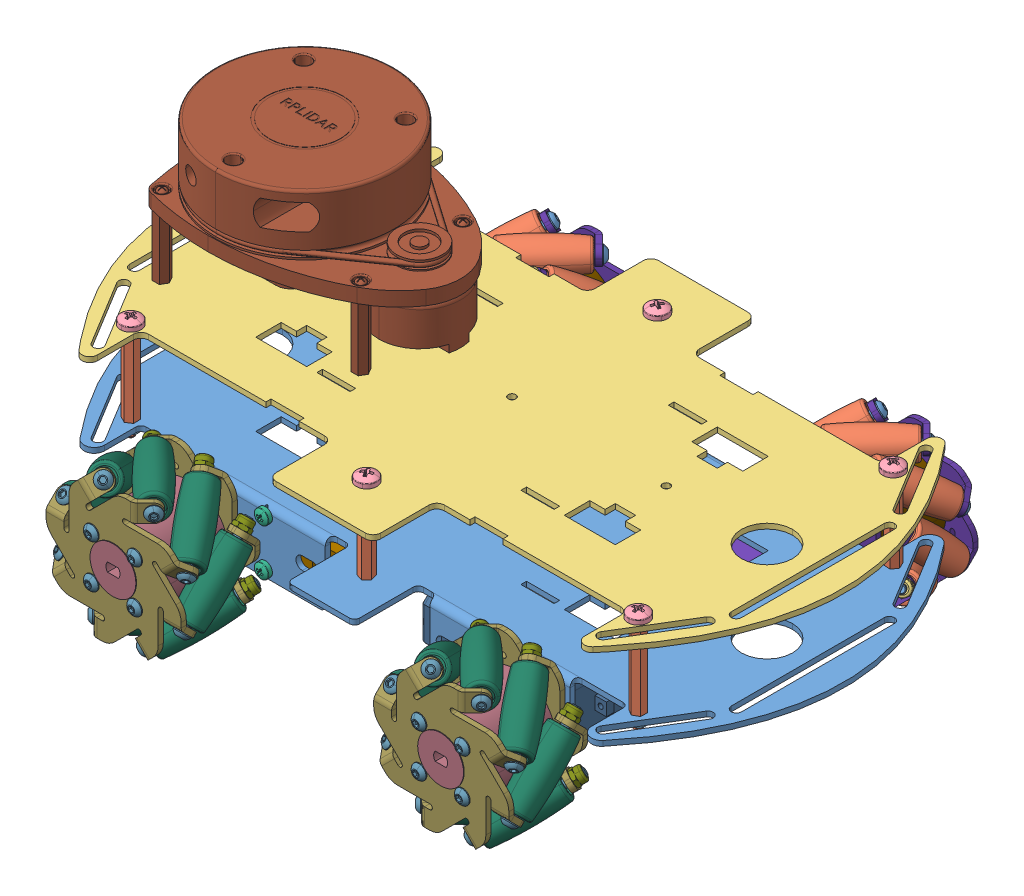
SolidWorks assembly mecanum_car, configuration Default. Lengths in mm.
Overall size (368.82 156.91 257.8).
187 component instances, 21 part files, 13 mates.
Components (placement in the parent):
- chassis.STEP-1: chassis.STEP [Default] at origin size (318.42 61.29 150)
  - chassis.STEP.STEP-1: chassis.STEP.STEP [Default] at origin size (318.42 61.29 150)
    - bottom chassis.STEP.STEP-1: bottom chassis.STEP.STEP [Default] at (-199.6129 0 0) x (1 0 0) z (0 0 -1) size (314.81 25.02 150)
    - supporting hexagon pillar.STEP.STEP-1: supporting hexagon pillar.STEP.STEP [Default] at (-299.1129 2 50) x (0.997179 0 -0.075054) z (0.075054 0 0.997179) size (4.8 36 5.42)
    - Copy of top chasis^chassis.STEP.STEP-1: Copy of top chasis^chassis.STEP.STEP [Default] at (-199.6129 32 0) size (318.42 2 150)
    - supporting hexagon pillar.STEP.STEP-2: supporting hexagon pillar.STEP.STEP [Default] at (-100.1129 2 50) x (0.482568 0 -0.875858) z (0.875858 0 0.482568) size (4.8 36 5.42)
    - supporting hexagon pillar.STEP.STEP-3: supporting hexagon pillar.STEP.STEP [Default] at (-100.1129 2 -50) x (0.886073 0 -0.463545) z (0.463545 0 0.886073) size (4.8 36 5.42)
    - supporting hexagon pillar.STEP.STEP-4: supporting hexagon pillar.STEP.STEP [Default] at (-299.1129 2 -50) x (0.482568 0 -0.875858) z (0.875858 0 0.482568) size (4.8 36 5.42)
    - pan head cross recess screw_iso_ISO 7045 - M4 x 5 - Z - 5N.STEP.STEP-1: pan head cross recess screw_iso_ISO 7045 - M4 x 5 - Z - 5N.STEP.STEP [Default] at (-100.1129 37.1 -50) x (0 -1 0) z (0.075054 0 0.997179) size (8.02 8 8)
    - pan head cross recess screw_iso_ISO 7045 - M4 x 5 - Z - 5N.STEP.STEP-2: pan head cross recess screw_iso_ISO 7045 - M4 x 5 - Z - 5N.STEP.STEP [Default] at (-100.1129 37.1 50) x (0 -1 0) z (0.075054 0 0.997179) size (8.02 8 8)
    - pan head cross recess screw_iso_ISO 7045 - M4 x 5 - Z - 5N.STEP.STEP-3: pan head cross recess screw_iso_ISO 7045 - M4 x 5 - Z - 5N.STEP.STEP [Default] at (-299.1129 37.1 -50) x (0 -1 0) z (0.075054 0 0.997179) size (8.02 8 8)
    - pan head cross recess screw_iso_ISO 7045 - M4 x 5 - Z - 5N.STEP.STEP-4: pan head cross recess screw_iso_ISO 7045 - M4 x 5 - Z - 5N.STEP.STEP [Default] at (-299.1129 37.1 50) x (0 -1 0) z (0.075054 0 0.997179) size (8.02 8 8)
    - hexagon thin nut (ch)_is_IS 1364-4 - M3-N.STEP.STEP-1: hexagon thin nut (ch)_is_IS 1364-4 - M3-N.STEP.STEP [Default] at (-299.1129 -1.8 -50) x (0.997179 0 -0.075054) z (0 -1 0) size (6.36 6.38 1.82)
    - hexagon thin nut (ch)_is_IS 1364-4 - M3-N.STEP.STEP-2: hexagon thin nut (ch)_is_IS 1364-4 - M3-N.STEP.STEP [Default] at (-299.1129 -1.8 50) x (0.997179 0 -0.075054) z (0 -1 0) size (6.36 6.38 1.82)
    - hexagon thin nut (ch)_is_IS 1364-4 - M3-N.STEP.STEP-3: hexagon thin nut (ch)_is_IS 1364-4 - M3-N.STEP.STEP [Default] at (-100.1129 -1.8 50) x (0.997179 0 -0.075054) z (0 -1 0) size (6.36 6.38 1.82)
    - hexagon thin nut (ch)_is_IS 1364-4 - M3-N.STEP.STEP-4: hexagon thin nut (ch)_is_IS 1364-4 - M3-N.STEP.STEP [Default] at (-100.1129 -1.8 -50) x (0.997179 0 -0.075054) z (0 -1 0) size (6.36 6.38 1.82)
    - pan head cross recess screw_iso_ISO 7045 - M3 x 30 - Z - 30S.STEP.STEP-1: pan head cross recess screw_iso_ISO 7045 - M3 x 30 - Z - 30S.STEP.STEP [Default] at (-155.6129 -20.0527 -55.1366) x (0 0 1) z (-0.913722 -0.40634 0) size (32.35 5.6 5.6)
    - pan head cross recess screw_iso_ISO 7045 - M3 x 30 - Z - 30S.STEP.STEP-2: pan head cross recess screw_iso_ISO 7045 - M3 x 30 - Z - 30S.STEP.STEP [Default] at (-155.6129 -1.6927 -55.1366) x (0 0 1) z (-0.913722 -0.40634 0) size (32.35 5.6 5.6)
    - pan head cross recess screw_iso_ISO 7045 - M3 x 30 - Z - 30S.STEP.STEP-3: pan head cross recess screw_iso_ISO 7045 - M3 x 30 - Z - 30S.STEP.STEP [Default] at (-243.6129 -20.0527 -55.1366) x (0 0 1) z (-0.913722 -0.40634 0) size (32.35 5.6 5.6)
    - pan head cross recess screw_iso_ISO 7045 - M3 x 30 - Z - 30S.STEP.STEP-4: pan head cross recess screw_iso_ISO 7045 - M3 x 30 - Z - 30S.STEP.STEP [Default] at (-243.6129 -1.6927 -55.1366) x (0 0 1) z (-0.913722 -0.40634 0) size (32.35 5.6 5.6)
    - pan head cross recess screw_iso_ISO 7045 - M3 x 30 - Z - 30S.STEP.STEP-5: pan head cross recess screw_iso_ISO 7045 - M3 x 30 - Z - 30S.STEP.STEP [Default] at (-243.6129 -20.0527 55.1366) x (0 0 -1) z (0.924865 -0.380295 0) size (32.35 5.6 5.6)
    - pan head cross recess screw_iso_ISO 7045 - M3 x 30 - Z - 30S.STEP.STEP-6: pan head cross recess screw_iso_ISO 7045 - M3 x 30 - Z - 30S.STEP.STEP [Default] at (-243.6129 -1.6927 55.1366) x (0 0 -1) z (0.924865 -0.380295 0) size (32.35 5.6 5.6)
    - pan head cross recess screw_iso_ISO 7045 - M3 x 30 - Z - 30S.STEP.STEP-7: pan head cross recess screw_iso_ISO 7045 - M3 x 30 - Z - 30S.STEP.STEP [Default] at (-155.6129 -20.0527 55.1366) x (0 0 -1) z (0.924865 -0.380295 0) size (32.35 5.6 5.6)
    - pan head cross recess screw_iso_ISO 7045 - M3 x 30 - Z - 30S.STEP.STEP-8: pan head cross recess screw_iso_ISO 7045 - M3 x 30 - Z - 30S.STEP.STEP [Default] at (-155.6129 -1.6927 55.1366) x (0 0 -1) z (0.924865 -0.380295 0) size (32.35 5.6 5.6)
    - hexagon thin nut (ch)_is_IS 1364-4 - M3-N.STEP.STEP-5: hexagon thin nut (ch)_is_IS 1364-4 - M3-N.STEP.STEP [Default] at (-155.6129 -20.1883 30.4366) x (0.939963 0.341277 0) z (0 0 -1) size (6.36 6.38 1.82)
    - hexagon thin nut (ch)_is_IS 1364-4 - M3-N.STEP.STEP-6: hexagon thin nut (ch)_is_IS 1364-4 - M3-N.STEP.STEP [Default] at (-155.6129 -1.6883 30.4366) x (0.939963 0.341277 0) z (0 0 -1) size (6.36 6.38 1.82)
    - hexagon thin nut (ch)_is_IS 1364-4 - M3-N.STEP.STEP-7: hexagon thin nut (ch)_is_IS 1364-4 - M3-N.STEP.STEP [Default] at (-243.6129 -20.057 30.4366) x (0.939963 0.341277 0) z (0 0 -1) size (6.36 6.38 1.82)
    - hexagon thin nut (ch)_is_IS 1364-4 - M3-N.STEP.STEP-8: hexagon thin nut (ch)_is_IS 1364-4 - M3-N.STEP.STEP [Default] at (-243.6129 -1.557 30.4366) x (0.939963 0.341277 0) z (0 0 -1) size (6.36 6.38 1.82)
    - hexagon thin nut (ch)_is_IS 1364-4 - M3-N.STEP.STEP-9: hexagon thin nut (ch)_is_IS 1364-4 - M3-N.STEP.STEP [Default] at (-243.6129 -20.1883 -30.4366) size (6.36 6.38 1.82)
    - hexagon thin nut (ch)_is_IS 1364-4 - M3-N.STEP.STEP-10: hexagon thin nut (ch)_is_IS 1364-4 - M3-N.STEP.STEP [Default] at (-243.6129 -1.6883 -30.4366) size (6.36 6.38 1.82)
    - hexagon thin nut (ch)_is_IS 1364-4 - M3-N.STEP.STEP-11: hexagon thin nut (ch)_is_IS 1364-4 - M3-N.STEP.STEP [Default] at (-155.6129 -20.057 -30.4366) size (6.36 6.38 1.82)
    - hexagon thin nut (ch)_is_IS 1364-4 - M3-N.STEP.STEP-12: hexagon thin nut (ch)_is_IS 1364-4 - M3-N.STEP.STEP [Default] at (-155.6129 -1.557 -30.4366) size (6.36 6.38 1.82)
    - supporting hexagon pillar.STEP.STEP-5: supporting hexagon pillar.STEP.STEP [Default] at (-199.6129 2 -57) x (0.376997 0 -0.926214) z (0.926214 0 0.376997) size (4.8 36 5.42)
    - supporting hexagon pillar.STEP.STEP-6: supporting hexagon pillar.STEP.STEP [Default] at (-199.6129 2 57) x (-0.715077 0 -0.699046) z (0.699046 0 -0.715077) size (4.8 36 5.42)
    - hexagon thin nut (ch)_is_IS 1364-4 - M3-N.STEP.STEP-13: hexagon thin nut (ch)_is_IS 1364-4 - M3-N.STEP.STEP [Default] at (-199.6129 -1.8 57) x (0.981594 0 -0.190977) z (0 -1 0) size (6.36 6.38 1.82)
    - hexagon thin nut (ch)_is_IS 1364-4 - M3-N.STEP.STEP-14: hexagon thin nut (ch)_is_IS 1364-4 - M3-N.STEP.STEP [Default] at (-199.6129 -1.8 -57) x (0.939935 0 -0.341353) z (0 -1 0) size (6.36 6.38 1.82)
    - pan head cross recess screw_iso_ISO 7045 - M4 x 5 - Z - 5N.STEP.STEP-5: pan head cross recess screw_iso_ISO 7045 - M4 x 5 - Z - 5N.STEP.STEP [Default] at (-199.6129 37.1 -57) x (0 -1 0) z (0.875858 0 0.482568) size (8.02 8 8)
    - pan head cross recess screw_iso_ISO 7045 - M4 x 5 - Z - 5N.STEP.STEP-6: pan head cross recess screw_iso_ISO 7045 - M4 x 5 - Z - 5N.STEP.STEP [Default] at (-199.6129 37.1 57) x (0 -1 0) z (0.463545 0 0.886073) size (8.02 8 8)
  - Motor1.step.STEP-1: Motor1.step.STEP [Default] at (-275.1129 -22.1883 -32.2366) size (66.5 22.5 38.5)
  - Motor2.step.STEP-1: Motor2.step.STEP [Default] at (-124.1129 0.443 -32.2366) x (-1 0 0) z (0 0 1) size (66.5 22.5 38.5)
  - Motor3.step.STEP-1: Motor3.step.STEP [Default] at (-275.1129 0.443 32.2366) x (1 0 0) z (0 0 -1) size (66.5 22.5 38.5)
  - Motor4.step.STEP-1: Motor4.step.STEP [Default] at (-124.1129 -22.1883 32.2366) x (-1 0 0) z (0 0 -1) size (66.5 22.5 38.5)
- rplidarA1.step-1: rplidarA1.step [Default] at (-280.315 65.1 0.5496) size (96.17 54.6 70)
- left_forward.STEP-1: left_forward.STEP [Default] at (-233.0265 -21.1144 212.4082) x (-0.184533 -0.709257 -0.680369) z (0.944404 -0.319631 0.077057) size (70.26 72.13 71.93)
  - Mirrormecanum wheels.STEP.STEP-1: Mirrormecanum wheels.STEP.STEP [Default] at (81.7182 87.2657 -41.8289) x (0.184533 -0.27212 -0.944404) z (-0.680369 -0.728807 0.077057) size (55.02 55.02 7.58)
  - Mirrorshaft.STEP.STEP-1: Mirrorshaft.STEP.STEP [Default] at (90.9032 97.1046 -42.8692) x (-0.184533 0.27212 0.944404) z (0.680369 0.728807 -0.077057) size (32 32 31.5)
  - Mirrormecanum wheels.STEP.STEP-2: Mirrormecanum wheels.STEP.STEP [Default] at (100.0882 106.9435 -43.9095) x (-0.709257 0.628323 -0.319631) z (0.680369 0.728807 -0.077057) size (55.02 55.02 7.58)
  - Mirrorbolt.STEP.STEP-1: Mirrorbolt.STEP.STEP [Default] at (87.2167 86.0621 -16.0538) x (-0.020427 0.959636 -0.280501) z (0.96794 0.089234 0.234795) size (38.65 5.7 5.7)
  - MirrorRoller.STEP.STEP-1: MirrorRoller.STEP.STEP [Default] at (86.8493 103.3226 -21.099) x (-0.020427 0.959636 -0.280501) z (0.96794 0.089234 0.234795) size (28 12 12)
  - Mirrorbolt.STEP.STEP-2: Mirrorbolt.STEP.STEP [Default] at (86.8189 76.965 -46.8491) x (0.680369 0.728807 -0.077057) z (-0.018616 -0.087924 -0.995953) size (38.65 5.7 5.7)
  - Mirrortorque nut 08_iso_ISO 10511-M3-N.STEP.STEP-1: Mirrortorque nut 08_iso_ISO 10511-M3-N.STEP.STEP [Default] at (110.0875 101.8903 -49.4844) x (-0.185961 0.06998 -0.980062) z (-0.680369 -0.728807 0.077057) size (6.36 6.38 3.91)
  - Mirrortorque nut 08_iso_ISO 10511-M3-N.STEP.STEP-2: Mirrortorque nut 08_iso_ISO 10511-M3-N.STEP.STEP [Default] at (86.1032 120.5687 -26.214) x (0.873571 0.153587 0.461828) z (0.020427 -0.959636 0.280501) size (6.36 6.38 3.91)
  - Mirrorbolt.STEP.STEP-3: Mirrorbolt.STEP.STEP [Default] at (98.9986 73.9021 -27.0356) x (0.034198 0.965566 0.257899) z (0.950888 0.047997 -0.305791) size (38.65 5.7 5.7)
  - Mirrorbolt.STEP.STEP-4: Mirrorbolt.STEP.STEP [Default] at (101.0077 69.945 -46.7228) x (0.350609 0.707763 0.613307) z (0.657996 0.279839 -0.699094) size (38.65 5.7 5.7)
  - Mirrorbolt.STEP.STEP-5: Mirrorbolt.STEP.STEP [Default] at (92.0671 76.5089 -63.5829) x (0.743455 0.337243 0.57753) z (0.260835 0.648951 -0.714722) size (38.65 5.7 5.7)
  - Mirrorbolt.STEP.STEP-6: Mirrorbolt.STEP.STEP [Default] at (77.414 89.7486 -67.7394) x (0.982614 0.071053 0.171526) z (-0.007942 0.939111 -0.343521) size (38.65 5.7 5.7)
  - Mirrorbolt.STEP.STEP-7: Mirrorbolt.STEP.STEP [Default] at (65.632 101.9086 -56.7575) x (0.927989 0.065123 -0.366873) z (0.00911 0.980348 0.197064) size (38.65 5.7 5.7)
  - Mirrorbolt.STEP.STEP-8: Mirrorbolt.STEP.STEP [Default] at (63.6229 105.8657 -37.0704) x (0.611578 0.322927 -0.722281) z (0.302003 0.748506 0.590367) size (38.65 5.7 5.7)
  - Mirrorbolt.STEP.STEP-9: Mirrorbolt.STEP.STEP [Default] at (72.5636 99.3019 -20.2103) x (0.218732 0.693446 -0.686505) z (0.699163 0.379394 0.605995) size (38.65 5.7 5.7)
  - Mirrortorque nut 08_iso_ISO 10511-M3-N.STEP.STEP-3: Mirrortorque nut 08_iso_ISO 10511-M3-N.STEP.STEP [Default] at (99.872 108.6244 -17.6135) x (0.997731 -0.018009 -0.064876) z (-0.034198 -0.965566 -0.257899) size (6.36 6.38 3.91)
  - Mirrortorque nut 08_iso_ISO 10511-M3-N.STEP.STEP-4: Mirrortorque nut 08_iso_ISO 10511-M3-N.STEP.STEP [Default] at (113.3894 95.2906 -24.3739) x (0.804741 0.107283 -0.583851) z (-0.350609 -0.707763 -0.613307) size (6.36 6.38 3.91)
  - Mirrortorque nut 08_iso_ISO 10511-M3-N.STEP.STEP-5: Mirrortorque nut 08_iso_ISO 10511-M3-N.STEP.STEP [Default] at (118.7372 88.378 -42.5352) x (0.407653 0.456068 -0.791089) z (-0.743455 -0.337243 -0.57753) size (6.36 6.38 3.91)
  - Mirrortorque nut 08_iso_ISO 10511-M3-N.STEP.STEP-6: Mirrortorque nut 08_iso_ISO 10511-M3-N.STEP.STEP [Default] at (112.7827 91.936 -61.4588) x (0.039074 0.824034 -0.565191) z (-0.982614 -0.071053 -0.171526) size (6.36 6.38 3.91)
  - Mirrortorque nut 08_iso_ISO 10511-M3-N.STEP.STEP-7: Mirrortorque nut 08_iso_ISO 10511-M3-N.STEP.STEP [Default] at (99.0139 103.8803 -70.0593) x (-0.085085 0.99563 -0.038487) z (-0.927989 -0.065123 0.366873) size (6.36 6.38 3.91)
  - Mirrortorque nut 08_iso_ISO 10511-M3-N.STEP.STEP-8: Mirrortorque nut 08_iso_ISO 10511-M3-N.STEP.STEP [Default] at (85.4965 117.2141 -63.2989) x (0.107904 0.870338 0.480488) z (-0.611578 -0.322927 0.722281) size (6.36 6.38 3.91)
  - Mirrortorque nut 08_iso_ISO 10511-M3-N.STEP.STEP-9: Mirrortorque nut 08_iso_ISO 10511-M3-N.STEP.STEP [Default] at (80.1487 124.1267 -45.1376) x (0.504993 0.521552 0.687725) z (-0.218732 -0.693446 0.686505) size (6.36 6.38 3.91)
  - MirrorRoller.STEP.STEP-2: MirrorRoller.STEP.STEP [Default] at (99.6137 91.2692 -22.3969) x (0.034198 0.965566 0.257899) z (0.950888 0.047997 -0.305791) size (28 12 12)
  - MirrorRoller.STEP.STEP-3: MirrorRoller.STEP.STEP [Default] at (107.3139 82.6752 -35.6916) x (0.350609 0.707763 0.613307) z (0.657996 0.279839 -0.699094) size (28 12 12)
  - MirrorRoller.STEP.STEP-4: MirrorRoller.STEP.STEP [Default] at (105.4392 82.5747 -53.1951) x (0.743455 0.337243 0.57753) z (0.260835 0.648951 -0.714722) size (28 12 12)
  - MirrorRoller.STEP.STEP-5: MirrorRoller.STEP.STEP [Default] at (95.0877 91.0266 -64.6542) x (0.982614 0.071053 0.171526) z (-0.007942 0.939111 -0.343521) size (28 12 12)
  - MirrorRoller.STEP.STEP-6: MirrorRoller.STEP.STEP [Default] at (82.3233 103.0799 -63.3563) x (0.927989 0.065123 -0.366873) z (0.00911 0.980348 0.197064) size (28 12 12)
  - MirrorRoller.STEP.STEP-7: MirrorRoller.STEP.STEP [Default] at (74.6231 111.674 -50.0616) x (0.611578 0.322927 -0.722281) z (0.302003 0.748506 0.590367) size (28 12 12)
  - MirrorRoller.STEP.STEP-8: MirrorRoller.STEP.STEP [Default] at (76.4978 111.7745 -32.5581) x (0.218732 0.693446 -0.686505) z (0.699163 0.379394 0.605995) size (28 12 12)
  - Mirrorbolt.STEP.STEP-10: Mirrorbolt.STEP.STEP [Default] at (83.6873 81.5831 -30.822) x (0.680369 0.728807 -0.077057) z (0.168933 -0.258274 -0.951187) size (38.65 5.7 5.7)
  - Mirrorbolt.STEP.STEP-11: Mirrorbolt.STEP.STEP [Default] at (71.6508 92.2461 -36.2463) x (0.680369 0.728807 -0.077057) z (0.340283 -0.407278 -0.847545) size (38.65 5.7 5.7)
  - Mirrorbolt.STEP.STEP-12: Mirrorbolt.STEP.STEP [Default] at (74.7824 87.6281 -52.2734) x (0.680369 0.728807 -0.077057) z (0.481066 -0.523448 -0.703262) size (38.65 5.7 5.7)
  - Mirrortorque nut 08_iso_ISO 10511-M3-N.STEP.STEP-10: Mirrortorque nut 08_iso_ISO 10511-M3-N.STEP.STEP [Default] at (98.051 112.5533 -54.9087) x (0.533825 -0.420797 0.733458) z (-0.680369 -0.728807 0.077057) size (6.36 6.38 3.91)
  - Mirrortorque nut 08_iso_ISO 10511-M3-N.STEP.STEP-11: Mirrortorque nut 08_iso_ISO 10511-M3-N.STEP.STEP [Default] at (106.9559 106.5083 -33.4573) x (0.321016 -0.201847 0.925314) z (-0.680369 -0.728807 0.077057) size (6.36 6.38 3.91)
  - Mirrortorque nut 08_iso_ISO 10511-M3-N.STEP.STEP-12: Mirrortorque nut 08_iso_ISO 10511-M3-N.STEP.STEP [Default] at (94.9194 117.1713 -38.8817) x (0.017858 0.088626 0.995905) z (-0.680369 -0.728807 0.077057) size (6.36 6.38 3.91)
- right_forward.STEP-1: right_forward.STEP [Default] at (-233.0265 -21.1144 -212.4082) x (-0.184533 -0.709257 0.680369) z (-0.944404 0.319631 0.077057) size (70.26 72.13 71.93)
  - MirrorMirrormecanum wheels.STEP.STEP.STEP-1: MirrorMirrormecanum wheels.STEP.STEP.STEP [Default] at (81.7182 87.2657 41.8289) x (0.184533 -0.27212 0.944404) z (0.680369 0.728807 0.077057) size (55.02 55.02 7.58)
  - MirrorMirrorshaft.STEP.STEP.STEP-1: MirrorMirrorshaft.STEP.STEP.STEP [Default] at (90.9032 97.1046 42.8692) x (-0.184533 0.27212 -0.944404) z (-0.680369 -0.728807 -0.077057) size (32 32 31.5)
  - MirrorMirrormecanum wheels.STEP.STEP.STEP-2: MirrorMirrormecanum wheels.STEP.STEP.STEP [Default] at (100.0882 106.9435 43.9095) x (-0.709257 0.628323 0.319631) z (-0.680369 -0.728807 -0.077057) size (55.02 55.02 7.58)
  - MirrorMirrorbolt.STEP.STEP.STEP-1: MirrorMirrorbolt.STEP.STEP.STEP [Default] at (87.2167 86.0621 16.0538) x (-0.020427 0.959636 0.280501) z (-0.96794 -0.089234 0.234795) size (38.65 5.7 5.7)
  - MirrorMirrorRoller.STEP.STEP.STEP-1: MirrorMirrorRoller.STEP.STEP.STEP [Default] at (86.8493 103.3226 21.099) x (-0.020427 0.959636 0.280501) z (-0.96794 -0.089234 0.234795) size (28 12 12)
  - MirrorMirrorbolt.STEP.STEP.STEP-2: MirrorMirrorbolt.STEP.STEP.STEP [Default] at (86.8189 76.965 46.8491) x (0.680369 0.728807 0.077057) z (0.018616 0.087924 -0.995953) size (38.65 5.7 5.7)
  - MirrorMirrortorque nut 08_iso_ISO 10511-M3-N.STEP.STEP.STEP-1: MirrorMirrortorque nut 08_iso_ISO 10511-M3-N.STEP.STEP.STEP [Default] at (110.0875 101.8903 49.4844) x (-0.185961 0.06998 0.980062) z (0.680369 0.728807 0.077057) size (6.36 6.36 3.91)
  - MirrorMirrortorque nut 08_iso_ISO 10511-M3-N.STEP.STEP.STEP-2: MirrorMirrortorque nut 08_iso_ISO 10511-M3-N.STEP.STEP.STEP [Default] at (86.1032 120.5687 26.214) x (0.873571 0.153587 -0.461828) z (-0.020427 0.959636 0.280501) size (6.36 6.36 3.91)
  - MirrorMirrorbolt.STEP.STEP.STEP-3: MirrorMirrorbolt.STEP.STEP.STEP [Default] at (98.9986 73.9021 27.0356) x (0.034198 0.965566 -0.257899) z (-0.950888 -0.047997 -0.305791) size (38.65 5.7 5.7)
  - MirrorMirrorbolt.STEP.STEP.STEP-4: MirrorMirrorbolt.STEP.STEP.STEP [Default] at (101.0077 69.945 46.7228) x (0.350609 0.707763 -0.613307) z (-0.657996 -0.279839 -0.699094) size (38.65 5.7 5.7)
  - MirrorMirrorbolt.STEP.STEP.STEP-5: MirrorMirrorbolt.STEP.STEP.STEP [Default] at (92.0671 76.5089 63.5829) x (0.743455 0.337243 -0.57753) z (-0.260835 -0.648951 -0.714722) size (38.65 5.7 5.7)
  - MirrorMirrorbolt.STEP.STEP.STEP-6: MirrorMirrorbolt.STEP.STEP.STEP [Default] at (77.414 89.7486 67.7394) x (0.982614 0.071053 -0.171526) z (0.007942 -0.939111 -0.343521) size (38.65 5.7 5.7)
  - MirrorMirrorbolt.STEP.STEP.STEP-7: MirrorMirrorbolt.STEP.STEP.STEP [Default] at (65.632 101.9086 56.7575) x (0.927989 0.065123 0.366873) z (-0.00911 -0.980348 0.197064) size (38.65 5.7 5.7)
  - MirrorMirrorbolt.STEP.STEP.STEP-8: MirrorMirrorbolt.STEP.STEP.STEP [Default] at (63.6229 105.8657 37.0704) x (0.611578 0.322927 0.722281) z (-0.302003 -0.748506 0.590367) size (38.65 5.7 5.7)
  - MirrorMirrorbolt.STEP.STEP.STEP-9: MirrorMirrorbolt.STEP.STEP.STEP [Default] at (72.5636 99.3019 20.2103) x (0.218732 0.693446 0.686505) z (-0.699163 -0.379394 0.605995) size (38.65 5.7 5.7)
  - MirrorMirrortorque nut 08_iso_ISO 10511-M3-N.STEP.STEP.STEP-3: MirrorMirrortorque nut 08_iso_ISO 10511-M3-N.STEP.STEP.STEP [Default] at (99.872 108.6244 17.6135) x (0.997731 -0.018009 0.064876) z (0.034198 0.965566 -0.257899) size (6.36 6.36 3.91)
  - MirrorMirrortorque nut 08_iso_ISO 10511-M3-N.STEP.STEP.STEP-4: MirrorMirrortorque nut 08_iso_ISO 10511-M3-N.STEP.STEP.STEP [Default] at (113.3894 95.2906 24.3739) x (0.804741 0.107283 0.583851) z (0.350609 0.707763 -0.613307) size (6.36 6.36 3.91)
  - MirrorMirrortorque nut 08_iso_ISO 10511-M3-N.STEP.STEP.STEP-5: MirrorMirrortorque nut 08_iso_ISO 10511-M3-N.STEP.STEP.STEP [Default] at (118.7372 88.378 42.5352) x (0.407653 0.456068 0.791089) z (0.743455 0.337243 -0.57753) size (6.36 6.36 3.91)
  - MirrorMirrortorque nut 08_iso_ISO 10511-M3-N.STEP.STEP.STEP-6: MirrorMirrortorque nut 08_iso_ISO 10511-M3-N.STEP.STEP.STEP [Default] at (112.7827 91.936 61.4588) x (0.039074 0.824034 0.565191) z (0.982614 0.071053 -0.171526) size (6.36 6.36 3.91)
  - MirrorMirrortorque nut 08_iso_ISO 10511-M3-N.STEP.STEP.STEP-7: MirrorMirrortorque nut 08_iso_ISO 10511-M3-N.STEP.STEP.STEP [Default] at (99.0139 103.8803 70.0593) x (-0.085085 0.99563 0.038487) z (0.927989 0.065123 0.366873) size (6.36 6.36 3.91)
  - MirrorMirrortorque nut 08_iso_ISO 10511-M3-N.STEP.STEP.STEP-8: MirrorMirrortorque nut 08_iso_ISO 10511-M3-N.STEP.STEP.STEP [Default] at (85.4965 117.2141 63.2989) x (0.107904 0.870338 -0.480488) z (0.611578 0.322927 0.722281) size (6.36 6.36 3.91)
  - MirrorMirrortorque nut 08_iso_ISO 10511-M3-N.STEP.STEP.STEP-9: MirrorMirrortorque nut 08_iso_ISO 10511-M3-N.STEP.STEP.STEP [Default] at (80.1487 124.1267 45.1376) x (0.504993 0.521552 -0.687725) z (0.218732 0.693446 0.686505) size (6.36 6.36 3.91)
  - MirrorMirrorRoller.STEP.STEP.STEP-2: MirrorMirrorRoller.STEP.STEP.STEP [Default] at (99.6137 91.2692 22.3969) x (0.034198 0.965566 -0.257899) z (-0.950888 -0.047997 -0.305791) size (28 12 12)
  - MirrorMirrorRoller.STEP.STEP.STEP-3: MirrorMirrorRoller.STEP.STEP.STEP [Default] at (107.3139 82.6752 35.6916) x (0.350609 0.707763 -0.613307) z (-0.657996 -0.279839 -0.699094) size (28 12 12)
  - MirrorMirrorRoller.STEP.STEP.STEP-4: MirrorMirrorRoller.STEP.STEP.STEP [Default] at (105.4392 82.5747 53.1951) x (0.743455 0.337243 -0.57753) z (-0.260835 -0.648951 -0.714722) size (28 12 12)
  - MirrorMirrorRoller.STEP.STEP.STEP-5: MirrorMirrorRoller.STEP.STEP.STEP [Default] at (95.0877 91.0266 64.6542) x (0.982614 0.071053 -0.171526) z (0.007942 -0.939111 -0.343521) size (28 12 12)
  - MirrorMirrorRoller.STEP.STEP.STEP-6: MirrorMirrorRoller.STEP.STEP.STEP [Default] at (82.3233 103.0799 63.3563) x (0.927989 0.065123 0.366873) z (-0.00911 -0.980348 0.197064) size (28 12 12)
  - MirrorMirrorRoller.STEP.STEP.STEP-7: MirrorMirrorRoller.STEP.STEP.STEP [Default] at (74.6231 111.674 50.0616) x (0.611578 0.322927 0.722281) z (-0.302003 -0.748506 0.590367) size (28 12 12)
  - MirrorMirrorRoller.STEP.STEP.STEP-8: MirrorMirrorRoller.STEP.STEP.STEP [Default] at (76.4978 111.7745 32.5581) x (0.218732 0.693446 0.686505) z (-0.699163 -0.379394 0.605995) size (28 12 12)
  - MirrorMirrorbolt.STEP.STEP.STEP-10: MirrorMirrorbolt.STEP.STEP.STEP [Default] at (83.6873 81.5831 30.822) x (0.680369 0.728807 0.077057) z (-0.168933 0.258274 -0.951187) size (38.65 5.7 5.7)
  - MirrorMirrorbolt.STEP.STEP.STEP-11: MirrorMirrorbolt.STEP.STEP.STEP [Default] at (71.6508 92.2461 36.2463) x (0.680369 0.728807 0.077057) z (-0.340283 0.407278 -0.847545) size (38.65 5.7 5.7)
  - MirrorMirrorbolt.STEP.STEP.STEP-12: MirrorMirrorbolt.STEP.STEP.STEP [Default] at (74.7824 87.6281 52.2734) x (0.680369 0.728807 0.077057) z (-0.481066 0.523448 -0.703262) size (38.65 5.7 5.7)
  - MirrorMirrortorque nut 08_iso_ISO 10511-M3-N.STEP.STEP.STEP-10: MirrorMirrortorque nut 08_iso_ISO 10511-M3-N.STEP.STEP.STEP [Default] at (98.051 112.5533 54.9087) x (0.533825 -0.420797 -0.733458) z (0.680369 0.728807 0.077057) size (6.36 6.36 3.91)
  - MirrorMirrortorque nut 08_iso_ISO 10511-M3-N.STEP.STEP.STEP-11: MirrorMirrortorque nut 08_iso_ISO 10511-M3-N.STEP.STEP.STEP [Default] at (106.9559 106.5083 33.4573) x (0.321016 -0.201847 -0.925314) z (0.680369 0.728807 0.077057) size (6.36 6.36 3.91)
  - MirrorMirrortorque nut 08_iso_ISO 10511-M3-N.STEP.STEP.STEP-12: MirrorMirrortorque nut 08_iso_ISO 10511-M3-N.STEP.STEP.STEP [Default] at (94.9194 117.1713 38.8817) x (0.017858 0.088626 -0.995905) z (0.680369 0.728807 0.077057) size (6.36 6.36 3.91)
- left_back.STEP-1: left_back.STEP [Default] at (-104.5265 -21.1144 212.4082) x (-0.184533 -0.709257 -0.680369) z (0.944404 -0.319631 0.077057) size (70.26 72.13 71.93)
  - Mirrormecanum wheels.STEP.STEP-1: Mirrormecanum wheels.STEP.STEP [Default] at (81.7182 87.2657 -41.8289) x (0.184533 -0.27212 -0.944404) z (-0.680369 -0.728807 0.077057) size (55.02 55.02 7.58)
  - Mirrorshaft.STEP.STEP-1: Mirrorshaft.STEP.STEP [Default] at (90.9032 97.1046 -42.8692) x (-0.184533 0.27212 0.944404) z (0.680369 0.728807 -0.077057) size (32 32 31.5)
  - Mirrormecanum wheels.STEP.STEP-2: Mirrormecanum wheels.STEP.STEP [Default] at (100.0882 106.9435 -43.9095) x (-0.709257 0.628323 -0.319631) z (0.680369 0.728807 -0.077057) size (55.02 55.02 7.58)
  - Mirrorbolt.STEP.STEP-1: Mirrorbolt.STEP.STEP [Default] at (87.2167 86.0621 -16.0538) x (-0.020427 0.959636 -0.280501) z (0.96794 0.089234 0.234795) size (38.65 5.7 5.7)
  - MirrorRoller.STEP.STEP-1: MirrorRoller.STEP.STEP [Default] at (86.8493 103.3226 -21.099) x (-0.020427 0.959636 -0.280501) z (0.96794 0.089234 0.234795) size (28 12 12)
  - Mirrorbolt.STEP.STEP-2: Mirrorbolt.STEP.STEP [Default] at (86.8189 76.965 -46.8491) x (0.680369 0.728807 -0.077057) z (-0.018616 -0.087924 -0.995953) size (38.65 5.7 5.7)
  - Mirrortorque nut 08_iso_ISO 10511-M3-N.STEP.STEP-1: Mirrortorque nut 08_iso_ISO 10511-M3-N.STEP.STEP [Default] at (110.0875 101.8903 -49.4844) x (-0.185961 0.06998 -0.980062) z (-0.680369 -0.728807 0.077057) size (6.36 6.38 3.91)
  - Mirrortorque nut 08_iso_ISO 10511-M3-N.STEP.STEP-2: Mirrortorque nut 08_iso_ISO 10511-M3-N.STEP.STEP [Default] at (86.1032 120.5687 -26.214) x (0.873571 0.153587 0.461828) z (0.020427 -0.959636 0.280501) size (6.36 6.38 3.91)
  - Mirrorbolt.STEP.STEP-3: Mirrorbolt.STEP.STEP [Default] at (98.9986 73.9021 -27.0356) x (0.034198 0.965566 0.257899) z (0.950888 0.047997 -0.305791) size (38.65 5.7 5.7)
  - Mirrorbolt.STEP.STEP-4: Mirrorbolt.STEP.STEP [Default] at (101.0077 69.945 -46.7228) x (0.350609 0.707763 0.613307) z (0.657996 0.279839 -0.699094) size (38.65 5.7 5.7)
  - Mirrorbolt.STEP.STEP-5: Mirrorbolt.STEP.STEP [Default] at (92.0671 76.5089 -63.5829) x (0.743455 0.337243 0.57753) z (0.260835 0.648951 -0.714722) size (38.65 5.7 5.7)
  - Mirrorbolt.STEP.STEP-6: Mirrorbolt.STEP.STEP [Default] at (77.414 89.7486 -67.7394) x (0.982614 0.071053 0.171526) z (-0.007942 0.939111 -0.343521) size (38.65 5.7 5.7)
  - Mirrorbolt.STEP.STEP-7: Mirrorbolt.STEP.STEP [Default] at (65.632 101.9086 -56.7575) x (0.927989 0.065123 -0.366873) z (0.00911 0.980348 0.197064) size (38.65 5.7 5.7)
  - Mirrorbolt.STEP.STEP-8: Mirrorbolt.STEP.STEP [Default] at (63.6229 105.8657 -37.0704) x (0.611578 0.322927 -0.722281) z (0.302003 0.748506 0.590367) size (38.65 5.7 5.7)
  - Mirrorbolt.STEP.STEP-9: Mirrorbolt.STEP.STEP [Default] at (72.5636 99.3019 -20.2103) x (0.218732 0.693446 -0.686505) z (0.699163 0.379394 0.605995) size (38.65 5.7 5.7)
  - Mirrortorque nut 08_iso_ISO 10511-M3-N.STEP.STEP-3: Mirrortorque nut 08_iso_ISO 10511-M3-N.STEP.STEP [Default] at (99.872 108.6244 -17.6135) x (0.997731 -0.018009 -0.064876) z (-0.034198 -0.965566 -0.257899) size (6.36 6.38 3.91)
  - Mirrortorque nut 08_iso_ISO 10511-M3-N.STEP.STEP-4: Mirrortorque nut 08_iso_ISO 10511-M3-N.STEP.STEP [Default] at (113.3894 95.2906 -24.3739) x (0.804741 0.107283 -0.583851) z (-0.350609 -0.707763 -0.613307) size (6.36 6.38 3.91)
  - Mirrortorque nut 08_iso_ISO 10511-M3-N.STEP.STEP-5: Mirrortorque nut 08_iso_ISO 10511-M3-N.STEP.STEP [Default] at (118.7372 88.378 -42.5352) x (0.407653 0.456068 -0.791089) z (-0.743455 -0.337243 -0.57753) size (6.36 6.38 3.91)
  - Mirrortorque nut 08_iso_ISO 10511-M3-N.STEP.STEP-6: Mirrortorque nut 08_iso_ISO 10511-M3-N.STEP.STEP [Default] at (112.7827 91.936 -61.4588) x (0.039074 0.824034 -0.565191) z (-0.982614 -0.071053 -0.171526) size (6.36 6.38 3.91)
  - Mirrortorque nut 08_iso_ISO 10511-M3-N.STEP.STEP-7: Mirrortorque nut 08_iso_ISO 10511-M3-N.STEP.STEP [Default] at (99.0139 103.8803 -70.0593) x (-0.085085 0.99563 -0.038487) z (-0.927989 -0.065123 0.366873) size (6.36 6.38 3.91)
  - Mirrortorque nut 08_iso_ISO 10511-M3-N.STEP.STEP-8: Mirrortorque nut 08_iso_ISO 10511-M3-N.STEP.STEP [Default] at (85.4965 117.2141 -63.2989) x (0.107904 0.870338 0.480488) z (-0.611578 -0.322927 0.722281) size (6.36 6.38 3.91)
  - Mirrortorque nut 08_iso_ISO 10511-M3-N.STEP.STEP-9: Mirrortorque nut 08_iso_ISO 10511-M3-N.STEP.STEP [Default] at (80.1487 124.1267 -45.1376) x (0.504993 0.521552 0.687725) z (-0.218732 -0.693446 0.686505) size (6.36 6.38 3.91)
  - MirrorRoller.STEP.STEP-2: MirrorRoller.STEP.STEP [Default] at (99.6137 91.2692 -22.3969) x (0.034198 0.965566 0.257899) z (0.950888 0.047997 -0.305791) size (28 12 12)
  - MirrorRoller.STEP.STEP-3: MirrorRoller.STEP.STEP [Default] at (107.3139 82.6752 -35.6916) x (0.350609 0.707763 0.613307) z (0.657996 0.279839 -0.699094) size (28 12 12)
  - MirrorRoller.STEP.STEP-4: MirrorRoller.STEP.STEP [Default] at (105.4392 82.5747 -53.1951) x (0.743455 0.337243 0.57753) z (0.260835 0.648951 -0.714722) size (28 12 12)
  - MirrorRoller.STEP.STEP-5: MirrorRoller.STEP.STEP [Default] at (95.0877 91.0266 -64.6542) x (0.982614 0.071053 0.171526) z (-0.007942 0.939111 -0.343521) size (28 12 12)
  - MirrorRoller.STEP.STEP-6: MirrorRoller.STEP.STEP [Default] at (82.3233 103.0799 -63.3563) x (0.927989 0.065123 -0.366873) z (0.00911 0.980348 0.197064) size (28 12 12)
  - MirrorRoller.STEP.STEP-7: MirrorRoller.STEP.STEP [Default] at (74.6231 111.674 -50.0616) x (0.611578 0.322927 -0.722281) z (0.302003 0.748506 0.590367) size (28 12 12)
  - MirrorRoller.STEP.STEP-8: MirrorRoller.STEP.STEP [Default] at (76.4978 111.7745 -32.5581) x (0.218732 0.693446 -0.686505) z (0.699163 0.379394 0.605995) size (28 12 12)
  - Mirrorbolt.STEP.STEP-10: Mirrorbolt.STEP.STEP [Default] at (83.6873 81.5831 -30.822) x (0.680369 0.728807 -0.077057) z (0.168933 -0.258274 -0.951187) size (38.65 5.7 5.7)
  - Mirrorbolt.STEP.STEP-11: Mirrorbolt.STEP.STEP [Default] at (71.6508 92.2461 -36.2463) x (0.680369 0.728807 -0.077057) z (0.340283 -0.407278 -0.847545) size (38.65 5.7 5.7)
  - Mirrorbolt.STEP.STEP-12: Mirrorbolt.STEP.STEP [Default] at (74.7824 87.6281 -52.2734) x (0.680369 0.728807 -0.077057) z (0.481066 -0.523448 -0.703262) size (38.65 5.7 5.7)
  - Mirrortorque nut 08_iso_ISO 10511-M3-N.STEP.STEP-10: Mirrortorque nut 08_iso_ISO 10511-M3-N.STEP.STEP [Default] at (98.051 112.5533 -54.9087) x (0.533825 -0.420797 0.733458) z (-0.680369 -0.728807 0.077057) size (6.36 6.38 3.91)
  - Mirrortorque nut 08_iso_ISO 10511-M3-N.STEP.STEP-11: Mirrortorque nut 08_iso_ISO 10511-M3-N.STEP.STEP [Default] at (106.9559 106.5083 -33.4573) x (0.321016 -0.201847 0.925314) z (-0.680369 -0.728807 0.077057) size (6.36 6.38 3.91)
  - Mirrortorque nut 08_iso_ISO 10511-M3-N.STEP.STEP-12: Mirrortorque nut 08_iso_ISO 10511-M3-N.STEP.STEP [Default] at (94.9194 117.1713 -38.8817) x (0.017858 0.088626 0.995905) z (-0.680369 -0.728807 0.077057) size (6.36 6.38 3.91)
- right_back.STEP-1: right_back.STEP [Default] at (-104.5265 -21.1144 -212.4082) x (-0.184533 -0.709257 0.680369) z (-0.944404 0.319631 0.077057) size (70.26 72.13 71.93)
  - MirrorMirrormecanum wheels.STEP.STEP.STEP-1: MirrorMirrormecanum wheels.STEP.STEP.STEP [Default] at (81.7182 87.2657 41.8289) x (0.184533 -0.27212 0.944404) z (0.680369 0.728807 0.077057) size (55.02 55.02 7.58)
  - MirrorMirrorshaft.STEP.STEP.STEP-1: MirrorMirrorshaft.STEP.STEP.STEP [Default] at (90.9032 97.1046 42.8692) x (-0.184533 0.27212 -0.944404) z (-0.680369 -0.728807 -0.077057) size (32 32 31.5)
  - MirrorMirrormecanum wheels.STEP.STEP.STEP-2: MirrorMirrormecanum wheels.STEP.STEP.STEP [Default] at (100.0882 106.9435 43.9095) x (-0.709257 0.628323 0.319631) z (-0.680369 -0.728807 -0.077057) size (55.02 55.02 7.58)
  - MirrorMirrorbolt.STEP.STEP.STEP-1: MirrorMirrorbolt.STEP.STEP.STEP [Default] at (87.2167 86.0621 16.0538) x (-0.020427 0.959636 0.280501) z (-0.96794 -0.089234 0.234795) size (38.65 5.7 5.7)
  - MirrorMirrorRoller.STEP.STEP.STEP-1: MirrorMirrorRoller.STEP.STEP.STEP [Default] at (86.8493 103.3226 21.099) x (-0.020427 0.959636 0.280501) z (-0.96794 -0.089234 0.234795) size (28 12 12)
  - MirrorMirrorbolt.STEP.STEP.STEP-2: MirrorMirrorbolt.STEP.STEP.STEP [Default] at (86.8189 76.965 46.8491) x (0.680369 0.728807 0.077057) z (0.018616 0.087924 -0.995953) size (38.65 5.7 5.7)
  - MirrorMirrortorque nut 08_iso_ISO 10511-M3-N.STEP.STEP.STEP-1: MirrorMirrortorque nut 08_iso_ISO 10511-M3-N.STEP.STEP.STEP [Default] at (110.0875 101.8903 49.4844) x (-0.185961 0.06998 0.980062) z (0.680369 0.728807 0.077057) size (6.36 6.36 3.91)
  - MirrorMirrortorque nut 08_iso_ISO 10511-M3-N.STEP.STEP.STEP-2: MirrorMirrortorque nut 08_iso_ISO 10511-M3-N.STEP.STEP.STEP [Default] at (86.1032 120.5687 26.214) x (0.873571 0.153587 -0.461828) z (-0.020427 0.959636 0.280501) size (6.36 6.36 3.91)
  - MirrorMirrorbolt.STEP.STEP.STEP-3: MirrorMirrorbolt.STEP.STEP.STEP [Default] at (98.9986 73.9021 27.0356) x (0.034198 0.965566 -0.257899) z (-0.950888 -0.047997 -0.305791) size (38.65 5.7 5.7)
  - MirrorMirrorbolt.STEP.STEP.STEP-4: MirrorMirrorbolt.STEP.STEP.STEP [Default] at (101.0077 69.945 46.7228) x (0.350609 0.707763 -0.613307) z (-0.657996 -0.279839 -0.699094) size (38.65 5.7 5.7)
  - MirrorMirrorbolt.STEP.STEP.STEP-5: MirrorMirrorbolt.STEP.STEP.STEP [Default] at (92.0671 76.5089 63.5829) x (0.743455 0.337243 -0.57753) z (-0.260835 -0.648951 -0.714722) size (38.65 5.7 5.7)
  - MirrorMirrorbolt.STEP.STEP.STEP-6: MirrorMirrorbolt.STEP.STEP.STEP [Default] at (77.414 89.7486 67.7394) x (0.982614 0.071053 -0.171526) z (0.007942 -0.939111 -0.343521) size (38.65 5.7 5.7)
  - MirrorMirrorbolt.STEP.STEP.STEP-7: MirrorMirrorbolt.STEP.STEP.STEP [Default] at (65.632 101.9086 56.7575) x (0.927989 0.065123 0.366873) z (-0.00911 -0.980348 0.197064) size (38.65 5.7 5.7)
  - MirrorMirrorbolt.STEP.STEP.STEP-8: MirrorMirrorbolt.STEP.STEP.STEP [Default] at (63.6229 105.8657 37.0704) x (0.611578 0.322927 0.722281) z (-0.302003 -0.748506 0.590367) size (38.65 5.7 5.7)
  - MirrorMirrorbolt.STEP.STEP.STEP-9: MirrorMirrorbolt.STEP.STEP.STEP [Default] at (72.5636 99.3019 20.2103) x (0.218732 0.693446 0.686505) z (-0.699163 -0.379394 0.605995) size (38.65 5.7 5.7)
  - MirrorMirrortorque nut 08_iso_ISO 10511-M3-N.STEP.STEP.STEP-3: MirrorMirrortorque nut 08_iso_ISO 10511-M3-N.STEP.STEP.STEP [Default] at (99.872 108.6244 17.6135) x (0.997731 -0.018009 0.064876) z (0.034198 0.965566 -0.257899) size (6.36 6.36 3.91)
  - MirrorMirrortorque nut 08_iso_ISO 10511-M3-N.STEP.STEP.STEP-4: MirrorMirrortorque nut 08_iso_ISO 10511-M3-N.STEP.STEP.STEP [Default] at (113.3894 95.2906 24.3739) x (0.804741 0.107283 0.583851) z (0.350609 0.707763 -0.613307) size (6.36 6.36 3.91)
  - MirrorMirrortorque nut 08_iso_ISO 10511-M3-N.STEP.STEP.STEP-5: MirrorMirrortorque nut 08_iso_ISO 10511-M3-N.STEP.STEP.STEP [Default] at (118.7372 88.378 42.5352) x (0.407653 0.456068 0.791089) z (0.743455 0.337243 -0.57753) size (6.36 6.36 3.91)
  - MirrorMirrortorque nut 08_iso_ISO 10511-M3-N.STEP.STEP.STEP-6: MirrorMirrortorque nut 08_iso_ISO 10511-M3-N.STEP.STEP.STEP [Default] at (112.7827 91.936 61.4588) x (0.039074 0.824034 0.565191) z (0.982614 0.071053 -0.171526) size (6.36 6.36 3.91)
  - MirrorMirrortorque nut 08_iso_ISO 10511-M3-N.STEP.STEP.STEP-7: MirrorMirrortorque nut 08_iso_ISO 10511-M3-N.STEP.STEP.STEP [Default] at (99.0139 103.8803 70.0593) x (-0.085085 0.99563 0.038487) z (0.927989 0.065123 0.366873) size (6.36 6.36 3.91)
  - MirrorMirrortorque nut 08_iso_ISO 10511-M3-N.STEP.STEP.STEP-8: MirrorMirrortorque nut 08_iso_ISO 10511-M3-N.STEP.STEP.STEP [Default] at (85.4965 117.2141 63.2989) x (0.107904 0.870338 -0.480488) z (0.611578 0.322927 0.722281) size (6.36 6.36 3.91)
  - MirrorMirrortorque nut 08_iso_ISO 10511-M3-N.STEP.STEP.STEP-9: MirrorMirrortorque nut 08_iso_ISO 10511-M3-N.STEP.STEP.STEP [Default] at (80.1487 124.1267 45.1376) x (0.504993 0.521552 -0.687725) z (0.218732 0.693446 0.686505) size (6.36 6.36 3.91)
  - MirrorMirrorRoller.STEP.STEP.STEP-2: MirrorMirrorRoller.STEP.STEP.STEP [Default] at (99.6137 91.2692 22.3969) x (0.034198 0.965566 -0.257899) z (-0.950888 -0.047997 -0.305791) size (28 12 12)
  - MirrorMirrorRoller.STEP.STEP.STEP-3: MirrorMirrorRoller.STEP.STEP.STEP [Default] at (107.3139 82.6752 35.6916) x (0.350609 0.707763 -0.613307) z (-0.657996 -0.279839 -0.699094) size (28 12 12)
  - MirrorMirrorRoller.STEP.STEP.STEP-4: MirrorMirrorRoller.STEP.STEP.STEP [Default] at (105.4392 82.5747 53.1951) x (0.743455 0.337243 -0.57753) z (-0.260835 -0.648951 -0.714722) size (28 12 12)
  - MirrorMirrorRoller.STEP.STEP.STEP-5: MirrorMirrorRoller.STEP.STEP.STEP [Default] at (95.0877 91.0266 64.6542) x (0.982614 0.071053 -0.171526) z (0.007942 -0.939111 -0.343521) size (28 12 12)
  - MirrorMirrorRoller.STEP.STEP.STEP-6: MirrorMirrorRoller.STEP.STEP.STEP [Default] at (82.3233 103.0799 63.3563) x (0.927989 0.065123 0.366873) z (-0.00911 -0.980348 0.197064) size (28 12 12)
  - MirrorMirrorRoller.STEP.STEP.STEP-7: MirrorMirrorRoller.STEP.STEP.STEP [Default] at (74.6231 111.674 50.0616) x (0.611578 0.322927 0.722281) z (-0.302003 -0.748506 0.590367) size (28 12 12)
  - MirrorMirrorRoller.STEP.STEP.STEP-8: MirrorMirrorRoller.STEP.STEP.STEP [Default] at (76.4978 111.7745 32.5581) x (0.218732 0.693446 0.686505) z (-0.699163 -0.379394 0.605995) size (28 12 12)
  - MirrorMirrorbolt.STEP.STEP.STEP-10: MirrorMirrorbolt.STEP.STEP.STEP [Default] at (83.6873 81.5831 30.822) x (0.680369 0.728807 0.077057) z (-0.168933 0.258274 -0.951187) size (38.65 5.7 5.7)
  - MirrorMirrorbolt.STEP.STEP.STEP-11: MirrorMirrorbolt.STEP.STEP.STEP [Default] at (71.6508 92.2461 36.2463) x (0.680369 0.728807 0.077057) z (-0.340283 0.407278 -0.847545) size (38.65 5.7 5.7)
  - MirrorMirrorbolt.STEP.STEP.STEP-12: MirrorMirrorbolt.STEP.STEP.STEP [Default] at (74.7824 87.6281 52.2734) x (0.680369 0.728807 0.077057) z (-0.481066 0.523448 -0.703262) size (38.65 5.7 5.7)
  - MirrorMirrortorque nut 08_iso_ISO 10511-M3-N.STEP.STEP.STEP-10: MirrorMirrortorque nut 08_iso_ISO 10511-M3-N.STEP.STEP.STEP [Default] at (98.051 112.5533 54.9087) x (0.533825 -0.420797 -0.733458) z (0.680369 0.728807 0.077057) size (6.36 6.36 3.91)
  - MirrorMirrortorque nut 08_iso_ISO 10511-M3-N.STEP.STEP.STEP-11: MirrorMirrortorque nut 08_iso_ISO 10511-M3-N.STEP.STEP.STEP [Default] at (106.9559 106.5083 33.4573) x (0.321016 -0.201847 -0.925314) z (0.680369 0.728807 0.077057) size (6.36 6.36 3.91)
  - MirrorMirrortorque nut 08_iso_ISO 10511-M3-N.STEP.STEP.STEP-12: MirrorMirrortorque nut 08_iso_ISO 10511-M3-N.STEP.STEP.STEP [Default] at (94.9194 117.1713 38.8817) x (0.017858 0.088626 -0.995905) z (0.680369 0.728807 0.077057) size (6.36 6.36 3.91)
Mates (geometry in assembly coordinates):
- Coincident1: coincident anti-aligned: plane of chassis.STEP-1/chassis.STEP.STEP-1/Copy of top chasis^chassis.STEP.STEP-1 through (-199.6129 34 0) normal (0 1 0); plane of rplidarA1.step-1 through (-280.315 34 0.5496) normal (0 -1 0)
- Coincident3: coincident anti-aligned: plane of chassis.STEP-1/Motor3.step.STEP-1 through (-260.6399 -9.1227 52.7366) normal (0 1 0); plane of left_forward.STEP-1/Mirrorshaft.STEP.STEP-1 through (-263.8629 -9.1227 39.5234) normal (0 -1 0)
- Concentric1: concentric anti-aligned: cylinder of chassis.STEP-1/Motor3.step.STEP-1 through (-263.8629 -10.8727 60.7366) axis (0 0 -1) radius 2.75; cylinder of left_forward.STEP-1/Mirrorshaft.STEP.STEP-1 through (-263.8629 -10.8727 39.5234) axis (0 0 1) radius 2.75
- Distance3: distance = 8 mm anti-aligned: plane of left_forward.STEP-1/Mirrorshaft.STEP.STEP-1 through (-263.8629 -10.8727 60.7366) normal (0 0 -1); plane of chassis.STEP-1/chassis.STEP.STEP-1/bottom chassis.STEP.STEP-1 through (-329.6129 51.9912 52.7366) normal (0 0 1)
- Coincident6: coincident anti-aligned: plane of chassis.STEP-1/Motor1.step.STEP-1 through (-260.6399 -9.1227 -52.7366) normal (0 1 0); plane of right_forward.STEP-1/MirrorMirrorshaft.STEP.STEP.STEP-1 through (-263.8629 -9.1227 -39.5234) normal (0 -1 0)
- Concentric2: concentric anti-aligned: cylinder of chassis.STEP-1/Motor1.step.STEP-1 through (-263.8629 -10.8727 -60.7366) axis (0 0 1) radius 2.75; cylinder of right_forward.STEP-1/MirrorMirrorshaft.STEP.STEP.STEP-1 through (-263.8629 -10.8727 -39.5234) axis (0 0 -1) radius 2.75
- Distance5: distance = 8 mm anti-aligned: plane of chassis.STEP-1/chassis.STEP.STEP-1/bottom chassis.STEP.STEP-1 through (-329.6129 51.9912 -52.7366) normal (0 0 -1); plane of right_forward.STEP-1/MirrorMirrorshaft.STEP.STEP.STEP-1 through (-263.8629 -10.8727 -60.7366) normal (0 0 1)
- Coincident10: coincident anti-aligned: plane of chassis.STEP-1/Motor4.step.STEP-1 through (-138.5858 -9.1227 52.7366) normal (0 1 0); plane of left_back.STEP-1/Mirrorshaft.STEP.STEP-1 through (-135.3629 -9.1227 39.5234) normal (0 -1 0)
- Concentric3: concentric anti-aligned: cylinder of chassis.STEP-1/Motor4.step.STEP-1 through (-135.3629 -10.8727 60.7366) axis (0 0 -1) radius 2.75; cylinder of left_back.STEP-1/Mirrorshaft.STEP.STEP-1 through (-135.3629 -10.8727 39.5234) axis (0 0 1) radius 2.75
- Distance7: distance = 8 mm anti-aligned: plane of chassis.STEP-1/chassis.STEP.STEP-1/bottom chassis.STEP.STEP-1 through (-329.6129 51.9912 52.7366) normal (0 0 1); plane of left_back.STEP-1/Mirrorshaft.STEP.STEP-1 through (-135.3629 -10.8727 60.7366) normal (0 0 -1)
- Coincident13: coincident anti-aligned: plane of chassis.STEP-1/Motor2.step.STEP-1 through (-138.5858 -9.1227 -52.7366) normal (0 1 0); plane of right_back.STEP-1/MirrorMirrorshaft.STEP.STEP.STEP-1 through (-135.3629 -9.1227 -39.5234) normal (0 -1 0)
- Concentric4: concentric anti-aligned: cylinder of chassis.STEP-1/Motor2.step.STEP-1 through (-135.3629 -10.8727 -60.7366) axis (0 0 1) radius 2.75; cylinder of right_back.STEP-1/MirrorMirrorshaft.STEP.STEP.STEP-1 through (-135.3629 -10.8727 -39.5234) axis (0 0 -1) radius 2.75
- Distance9: distance = 8 mm anti-aligned: plane of chassis.STEP-1/chassis.STEP.STEP-1/bottom chassis.STEP.STEP-1 through (-329.6129 51.9912 -52.7366) normal (0 0 -1); plane of right_back.STEP-1/MirrorMirrorshaft.STEP.STEP.STEP-1 through (-135.3629 -10.8727 -60.7366) normal (0 0 1)
